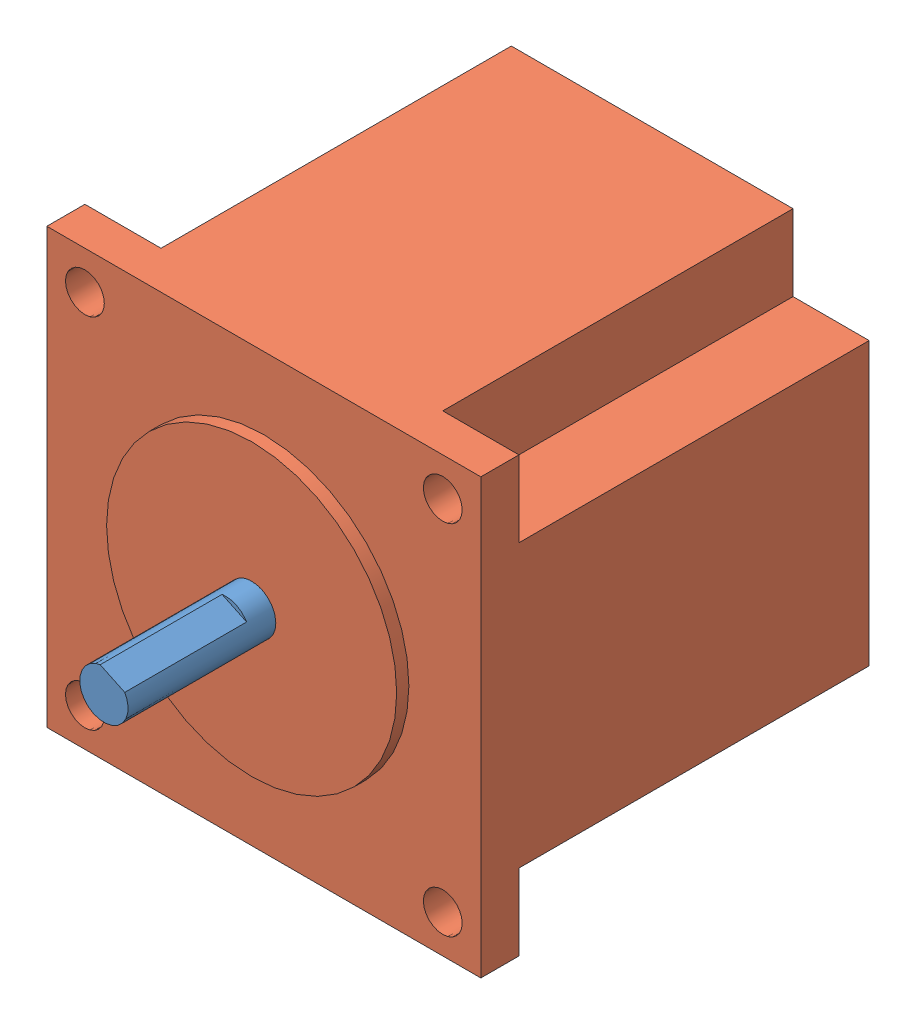
SolidWorks assembly 23HM20-0384S, configuration 23HM20-0384S. Lengths in mm.
Overall size (57 57 72).
2 component instances, 2 part files, 2 mates.
Components (placement in the parent):
- Shaft-1: Shaft [23HM20-0384S] x (0.903842 -0.427867 0) z (0 0 1) size (6.35 6.35 72)
- Body-1: Body [23HM20-0384S] at origin size (57 57 52.6)
Mates (geometry in assembly coordinates):
- Concentric2: concentric anti-aligned: cylinder of Shaft-1 through (0 0 21) axis (0 0 -1) radius 3.175; cylinder of Body-1 through (0 0 -51) axis (0 0 1) radius 3.175
- Coincident2: coincident aligned: plane of Shaft-1 through (0 0 0) normal (0 0 1); plane of Body-1 through (0 0 0) normal (0 0 1)
